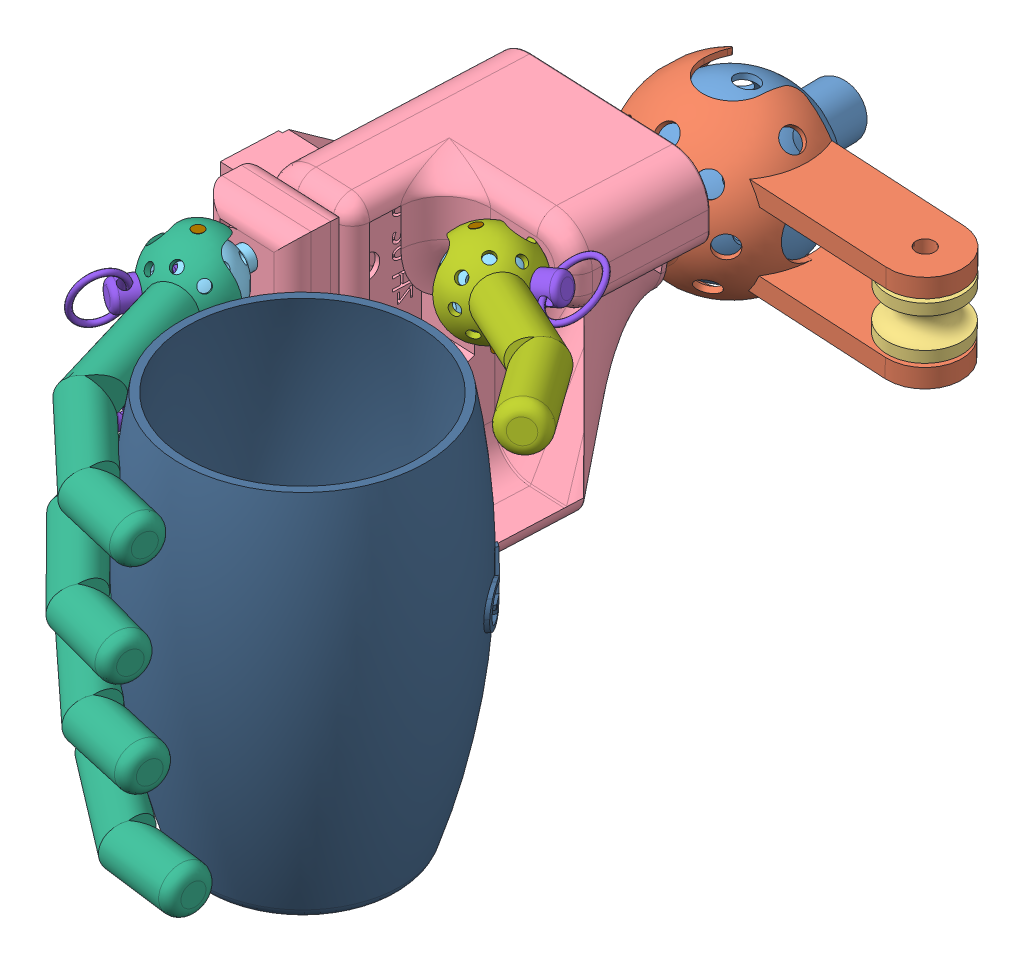
SolidWorks assembly рука1, configuration По умолчанию. Lengths in mm.
Overall size (138.26 142.12 262.34).
25 component instances, 10 part files, 0 mates.
Components (placement in the parent):
- Wrist (Ball)-1: Wrist (Ball) [По умолчанию] at (182.0296 -28.2692 -67.9871) x (-0.656699 0.754148 -0.002823) z (-0.736943 -0.640913 0.214816) size (42 55.8 41.57)
- Wrist (Socket)-1: Wrist (Socket) [По умолчанию] at (182.9518 -27.283 -67.3337) x (0.998988 -0.012031 0.043338) z (-0.012019 -0.999928 -0.000521) size (89.1 37 45.25)
- Wrist (Pulley)-1: Wrist (Pulley) [По умолчанию] at (237.9525 -27.9619 -63.9467) x (0.871987 -0.010226 -0.489423) z (-0.012019 -0.999928 -0.000521) size (20 20 14)
- Finger (Hand)-2-1: Finger (Hand)-2 [По умолчанию] at (204.0737 -34.1324 42.9554) x (0 1 0) z (-0.043342 0 0.99906) size (100.4 77.16 97.92)
- Finger (Ball)-1: Finger (Ball) [По умолчанию] at (177.0223 12.717 69.3472) x (0.001347 -0.999999 0.000058) z (0.999059 0.001349 0.043341) size (20 22.54 19.77)
- Finger (Socket)-1: Finger (Socket) [По умолчанию] at (177.0216 13.217 69.3471) x (-0.676647 -0.708007 0.202175) z (-0.678552 0.706205 0.202093) size (38.39 91.08 37.87)
- Finger (Ball)-2: Finger (Ball) [По умолчанию] at (177.0223 -14.783 69.3472) x (-0.999059 -0.001349 -0.043341) z (0.001347 -0.999999 0.000058) size (20 22.54 19.77)
- Finger (Socket)-2: Finger (Socket) [По умолчанию] at (177.0216 -14.283 69.3471) x (-0.682702 -0.708017 0.180638) z (-0.684608 0.706196 0.180555) size (38.39 91.08 37.87)
- Finger (Ball)-3: Finger (Ball) [По умолчанию] at (177.0223 -39.783 69.3472) x (0 -1 0) z (0.99906 0 0.043342) size (20 22.54 19.77)
- Finger (Socket)-3: Finger (Socket) [По умолчанию] at (177.0223 -39.283 69.3472) x (-0.675394 -0.707107 0.209388) z (-0.675394 0.707107 0.209388) size (38.39 91.08 37.87)
- Finger (Ball)-4: Finger (Ball) [По умолчанию] at (177.0223 -67.283 69.3472) x (-0.706442 -0.707107 -0.030647) z (0.706442 -0.707107 0.030647) size (20 22.54 19.77)
- Finger (Socket)-4: Finger (Socket) [По умолчанию] at (177.0223 -67.283 69.3472) x (-0.652517 -0.707107 0.272436) z (-0.652517 0.707107 0.272436) size (38.39 91.08 37.87)
- Finger (Ball)-5: Finger (Ball) [По умолчанию] at (216.2207 12.717 31.01) x (0.872657 -0.486864 0.037858) z (0.486406 0.873478 0.021101) size (20 22.54 19.77)
- Thumb (Socket)-1: Thumb (Socket) [По умолчанию] at (216.0841 13.1979 31.0041) x (0.155949 0.771796 -0.61645) z (0.5422 -0.588546 -0.599694) size (24.44 80.4 23.92)
- Wrist (Lock Pin)-1: Wrist (Lock Pin) [По умолчанию] at (176.5621 12.7152 71.3719) x (0.335008 0.924534 0.181679) z (-0.475466 -0.000589 0.879734) size (19.35 7.53 29.68)
- Wrist (Lock Pin)-2: Wrist (Lock Pin) [По умолчанию] at (175.7048 -13.6259 70.8953) x (-0.577095 -0.744152 -0.336452) z (-0.503058 -0.000627 0.864252) size (19.35 7.53 29.68)
- Wrist (Lock Pin)-3: Wrist (Lock Pin) [По умолчанию] at (175.4372 -39.1497 70.7728) x (0.141994 -0.987038 0.074787) z (-0.466006 0 0.884782) size (19.35 7.53 29.68)
- Wrist (Lock Pin)-4: Wrist (Lock Pin) [По умолчанию] at (176.8834 -67.6166 71.4524) x (0.111746 0.992675 0.045919) z (-0.380081 0 0.924953) size (19.35 7.53 29.68)
- Wrist (Lock Pin)-5: Wrist (Lock Pin) [По умолчанию] at (217.7543 14.4451 30.5377) x (0.321086 -0.293741 0.900344) z (0.932898 0.261838 -0.24727) size (19.35 7.53 29.68)
- Finger (Pivot Pin, Short)-1: Finger (Pivot Pin, Short) [По умолчанию] at (177.0216 13.217 69.3471) x (0.750469 0.00105 0.660905) z (0.001347 -0.999999 0.000058) size (4 4 26)
- Finger (Pivot Pin, Short)-2: Finger (Pivot Pin, Short) [По умолчанию] at (177.0216 -14.283 69.3471) x (0.553482 0.000697 -0.832861) z (-0.001347 0.999999 -0.000058) size (4 4 26)
- Finger (Pivot Pin, Short)-3: Finger (Pivot Pin, Short) [По умолчанию] at (177.0223 -39.283 69.3472) x (0.976062 0 0.21749) z (0 -1 0) size (4 4 26)
- Finger (Pivot Pin, Short)-4: Finger (Pivot Pin, Short) [По умолчанию] at (177.0223 -67.283 69.3472) x (0.692561 0 -0.721359) z (0 1 0) size (4 4 26)
- Finger (Pivot Pin, Short)-5: Finger (Pivot Pin, Short) [По умолчанию] at (216.0841 13.1979 31.0041) x (-0.71018 -0.193307 0.676961) z (0.27312 -0.961907 0.011849) size (4 4 26)
- Стакан-1: Стакан [По умолчанию] at (231.0311 -77.283 95.4622) x (-0.810088 0 -0.586308) z (0.586308 0 -0.810088) size (72.92 104.75 74.31)
